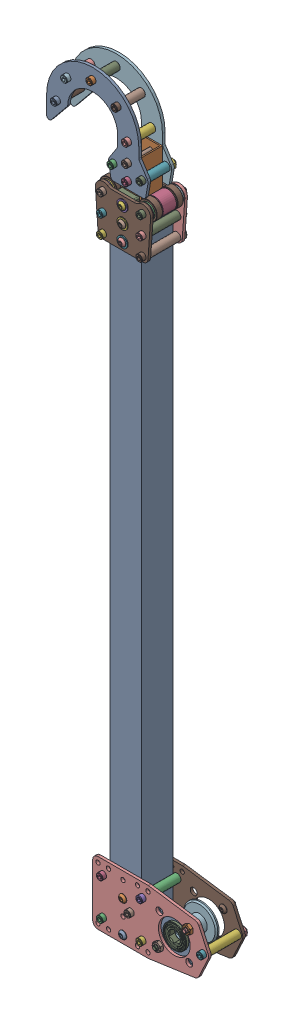
SolidWorks assembly 1 Stage Climber-In-A-Box, configuration Default. Lengths in mm.
Overall size (201.61 890.82 60.32).
6 component instances, 6 part files, 15 mates.
Components (placement in the parent):
- 1.5in Winch Kit-1: 1.5in Winch Kit [Default] at (-17.4625 0 -41.275) size (139.7 76.2 60.32)
- Hook-1: Hook [Default] at (-70.2653 35.4458 -715.1468) size (122.24 106.36 42.93)
- Stage 1 Rollers-1: Stage 1 Rollers [Default] at (-70.2653 32.0848 -730.9861) size (69.53 61.8 55.63)
- Nylon Bearing Clamp-1: Nylon Bearing Clamp [Default] at (-70.2653 -153.0566 -715.1468) size (34.04 38.1 34.04)
- Stage 1 Tube-1: Stage 1 Tube [Default] at origin size (38.1 762 38.1)
- 1x1 Simple Example Tube_2-1: 1x1 Simple Example Tube_2 [Default] at (19.05 60.5579 -19.05) size (25.4 762 25.4)
Mates (geometry in assembly coordinates):
- Concentric1: concentric aligned: cylinder of Hook-1 through (19.05 793.9829 33.401) axis (0 0 1) radius 2.413; cylinder of 1x1 Simple Example Tube_2-1 through (19.05 793.9829 -31.75) axis (0 0 1) radius 2.5527
- Coincident1: coincident anti-aligned: plane of Hook-1 through (36.5125 803.5079 -31.75) normal (0 0 1); plane of 1x1 Simple Example Tube_2-1 through (6.35 822.5579 -31.75) normal (0 0 -1)
- Width1: width anti-aligned: plane of Stage 1 Tube-1 through (0 762 -38.1) normal (0 0 -1); plane of Stage 1 Tube-1 through (0 762 0) normal (0 0 1); plane of Stage 1 Rollers-1 through (19.05 733.425 -32.258) normal (0 0 1); plane of Stage 1 Rollers-1 through (19.05 733.425 -5.842) normal (0 0 -1)
- Width2: width anti-aligned: plane of Stage 1 Tube-1 through (0 762 0) normal (-1 0 0); plane of Stage 1 Tube-1 through (38.1 762 0) normal (1 0 0); plane of Stage 1 Rollers-1 through (34.925 723.9 -38.1) normal (1 0 0); plane of Stage 1 Rollers-1 through (3.175 723.9 -38.1) normal (-1 0 0)
- Concentric2: concentric aligned: cylinder of Hook-1 through (19.05 813.0329 33.401) axis (0 0 1) radius 2.413; cylinder of 1x1 Simple Example Tube_2-1 through (19.05 813.0329 -31.75) axis (0 0 1) radius 2.5527
- Concentric3: concentric anti-aligned: cylinder of Stage 1 Rollers-1 through (19.05 733.425 -41.275) axis (0 0 -1) radius 6.3246; cylinder of Stage 1 Tube-1 through (19.05 733.425 -38.1) axis (0 0 1) radius 2.5527
- Coincident2: coincident aligned: plane of Nylon Bearing Clamp-1 through (6.35 60.5579 -2.032) normal (0 -1 0); plane of 1x1 Simple Example Tube_2-1 through (19.05 60.5579 -19.05) normal (0 -1 0)
- Coincident3: coincident anti-aligned: plane of Nylon Bearing Clamp-1 through (6.35 79.6079 -19.05) normal (1 0 0); plane of 1x1 Simple Example Tube_2-1 through (6.35 822.5579 -31.75) normal (-1 0 0)
- Width3: width aligned: plane of Nylon Bearing Clamp-1 through (6.35 60.5579 -6.223) normal (0.017452 0 -0.999848); plane of Nylon Bearing Clamp-1 through (6.35 60.5579 -31.877) normal (0.017452 0 0.999848); plane of 1x1 Simple Example Tube_2-1 through (6.35 822.5579 -6.35) normal (0 0 1); plane of 1x1 Simple Example Tube_2-1 through (6.35 822.5579 -31.75) normal (0 0 -1)
- Width4: width anti-aligned: plane of Stage 1 Tube-1 through (0 762 -38.1) normal (0 0 -1); plane of Stage 1 Tube-1 through (0 762 0) normal (0 0 1); plane of 1.5in Winch Kit-1 through (-11.1125 6.35 -38.1) normal (0 0 1); plane of 1.5in Winch Kit-1 through (-11.1125 6.35 0) normal (0 0 -1)
- Concentric4: concentric anti-aligned: cylinder of 1.5in Winch Kit-1 through (19.05 9.525 -43.8404) axis (0 0 -1) radius 2.413; cylinder of Stage 1 Tube-1 through (19.05 9.525 -38.1) axis (0 0 1) radius 2.5527
- Concentric5: concentric aligned: cylinder of 1.5in Winch Kit-1 through (28.575 38.1 39.751) axis (0 0 1) radius 2.413; cylinder of Stage 1 Tube-1 through (28.575 38.1 -38.1) axis (0 0 1) radius 2.5527
- Width5: width anti-aligned: plane of Stage 1 Tube-1 through (0 762 0) normal (0 0 1); plane of Stage 1 Tube-1 through (0 762 -38.1) normal (0 0 -1); plane of 1x1 Simple Example Tube_2-1 through (6.35 822.5579 -31.75) normal (0 0 -1); plane of 1x1 Simple Example Tube_2-1 through (6.35 822.5579 -6.35) normal (0 0 1)
- Width6: width aligned: plane of Stage 1 Tube-1 through (0 762 0) normal (-1 0 0); plane of Stage 1 Tube-1 through (38.1 762 0) normal (1 0 0); plane of 1x1 Simple Example Tube_2-1 through (6.35 822.5579 -31.75) normal (-1 0 0); plane of 1x1 Simple Example Tube_2-1 through (31.75 822.5579 -31.75) normal (1 0 0)
- Tangent2: tangent anti-aligned: cylinder of Hook-1 through (37.0108 787.6329 -6.35) axis (0 0 1) radius 3.175; cylinder of Stage 1 Rollers-1 through (42.8135 774.7 -3.048) axis (0 0 1) radius 11
